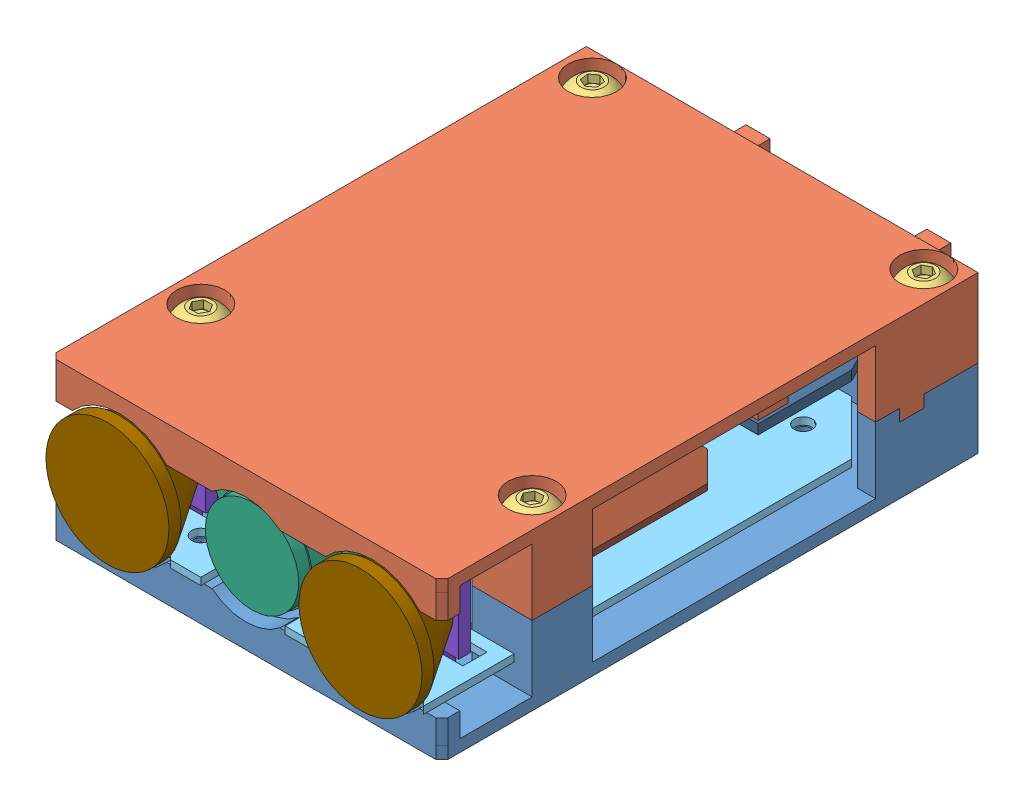
SolidWorks assembly master, configuration Default. Lengths in mm.
Overall size (68.08 28.52 102).
16 component instances, 11 part files, 37 mates.
Components (placement in the parent):
- chassi_master_inf-1: chassi_master_inf [Default] at (0 -0.5 -40) size (65 13 100)
- chassi_master_sup-1: chassi_master_sup [Default] at (0 25.5 -40) x (-1 0 0) z (0 0 1) size (65 15 100)
- Socket Button Head Screw_ISO-6: Socket Button Head Screw_ISO [ISO 7380 - M4 x 16 --- 16N] at (-27.5 25.1 -15) x (0 -1 0) z (0.03716 0 0.999309) size (18.2 7.6 7.6)
- Socket Button Head Screw_ISO-7: Socket Button Head Screw_ISO [ISO 7380 - M4 x 16 --- 16N] at (27.5 25.1 -15) x (0 -1 0) z (0.045545 0 0.998962) size (18.2 7.6 7.6)
- SUB9_macho-1: SUB9_macho [Default] at (0 6 -84) x (-1 0 0) z (0 0 -1) size (31 12.5 11.5)
- Socket Button Head Screw_ISO-8: Socket Button Head Screw_ISO [ISO 7380 - M4 x 16 --- 16N] at (-27.5 25.1 -80) x (0 -1 0) z (0.606475 0 0.795103) size (18.2 7.6 7.6)
- Socket Button Head Screw_ISO-9: Socket Button Head Screw_ISO [ISO 7380 - M4 x 16 --- 16N] at (27.5 25.1 -80) x (0 -1 0) z (-0.999509 0 -0.031349) size (18.2 7.6 7.6)
- PCB_master-1: PCB_master [Default] at (0 5.5 -34.5) size (60 1.2 80)
- camera-1: camera [Default] at (0 12.5 -19) x (0 1 0) z (0 0 1) size (21 26 23)
- bateria_9V-1: bateria_9V [Default] at (-14.65 14.5 -74.5) x (0 1 0) z (1 0 0) size (15.6 48.5 26.7)
- luz-1: luz [Default] at (-21 12.5 -5.8) size (11 16 3)
- luz-2: luz [Default] at (21 12.5 -5.8) size (11 16 3)
- lente-1: lente [Default] at (-21 12.5 -3.8) x (0 0 -1) z (0.999866 0.016372 0) size (10.8 20.4 20.4)
- lente-2: lente [Default] at (21 12.5 -3.8) x (0 0 -1) z (0.805945 0.59199 0) size (10.8 20.4 20.4)
- PCB_master2-1: PCB_master2 [Default] at (14.5 19.5 -59.25) x (0 0 1) z (1 0 0) size (18.5 1.6 31)
- XBee-1: XBee [Default] at (14.2823 10.9107 -38.7844) size (22 11 26)
Mates (geometry in assembly coordinates):
- Parallel3: parallel: plane of chassi_master_inf-1 through (-32.5 1.5 5) normal (0 1 0)
- Coincident38: coincident anti-aligned: plane of chassi_master_inf-1 through (-32.5 12.5 -20) normal (0 1 0); plane of chassi_master_sup-1 through (-32.5 12.5 -20) normal (0 -1 0)
- Coincident39: coincident aligned: plane of chassi_master_inf-1 through (-32.5 1.5 5) normal (0 0 1); plane of chassi_master_sup-1 through (32.5 23.5 5) normal (0 0 1)
- Coincident40: coincident aligned: plane of chassi_master_inf-1 through (-32.5 1.5 -85) normal (-1 0 0); plane of chassi_master_sup-1 through (-32.5 23.5 -85) normal (-1 0 0)
- Concentric262: concentric aligned: cylinder of chassi_master_inf-1; cylinder of SUB9_macho-1
- Concentric263: concentric aligned: cylinder of chassi_master_inf-1; cylinder of SUB9_macho-1
- Coincident513: coincident anti-aligned: plane of chassi_master_inf-1 through (-13 8.5 -84) normal (0 0 -1); plane of SUB9_macho-1 through (15.5 -0.25 -84) normal (0 0 1)
- Concentric264: concentric aligned: unknown of chassi_master_sup-1
- Concentric265: concentric aligned: unknown of chassi_master_sup-1
- Coincident514: coincident anti-aligned: unknown of chassi_master_sup-1
- Coincident515: coincident anti-aligned: unknown of chassi_master_sup-1
- Concentric266: concentric aligned: cylinder of chassi_master_inf-1; cylinder of PCB_master-1
- Concentric267: concentric aligned: cylinder of chassi_master_inf-1; cylinder of PCB_master-1
- Coincident516: coincident anti-aligned: plane of chassi_master_inf-1 through (10.5 5.5 2) normal (0 1 0); plane of PCB_master-1 through (-30 5.5 -20.5) normal (0 -1 0)
- Width1: width: plane of camera-1 through (-10.5 23 -3) normal (0 1 0); plane of camera-1 through (-10.5 2 -3) normal (0 -1 0); plane of chassi_master_inf-1 through (-32.5 1.5 5) normal (0 1 0); plane of chassi_master_sup-1 through (32.5 23.5 5) normal (0 -1 0)
- Width2: width: plane of camera-1 through (10.5 2 -3) normal (1 0 0); plane of camera-1 through (-10.5 2 -3) normal (-1 0 0); plane of chassi_master_inf-1 through (18.5 10.5 -13) normal (-1 0 0); plane of chassi_master_sup-1 through (-18.5 10.5 -13) normal (1 0 0)
- Coincident518: coincident anti-aligned: plane of PCB_master-1 through (-10.5 -3.3 -19) normal (0 0 1); plane of camera-1 through (10.5 12.5 -19) normal (0 0 -1)
- Coincident519: coincident anti-aligned: plane of PCB_master-1 through (-30 6.7 -20.5) normal (0 1 0); plane of bateria_9V-1 through (-28 6.7 -26) normal (0 -1 0)
- Distance2: distance = 2 mm aligned: plane of PCB_master-1 through (-30 6.7 -74.5) normal (-1 0 0); plane of bateria_9V-1 through (-28 6.7 -26) normal (-1 0 0)
- Coincident533: coincident aligned: plane of PCB_master-1 through (-30 6.7 -74.5) normal (0 0 -1); plane of bateria_9V-1 through (-1.3 6.7 -74.5) normal (0 0 -1)
- Concentric268: concentric anti-aligned: cylinder of luz-1; cylinder of lente-1
- Concentric269: concentric anti-aligned: cylinder of luz-2; cylinder of lente-2
- Coincident522: coincident anti-aligned: plane of luz-2 through (15.5 2 -3.8) normal (0 0 1); plane of lente-2 through (17.3168 9.7946 -3.8) normal (0 0 -1)
- Coincident524: coincident anti-aligned: plane of luz-1 through (-26.5 2 -3.8) normal (0 0 1); plane of lente-1 through (-25.5694 12.4252 -3.8) normal (0 0 -1)
- Coincident525: coincident aligned: plane of luz-1 through (-26.5 2 -5.8) normal (0 0 -1); plane of luz-2 through (15.5 2 -5.8) normal (0 0 -1)
- Coincident526: coincident aligned: plane of luz-1 through (-26.5 18 -3.8) normal (0 1 0); plane of luz-2 through (15.5 18 -3.8) normal (0 1 0)
- Symmetric1: symmetric aligned: plane of chassi_master_inf-1 through (32.5 12.5 -20) normal (0 1 0); plane of luz-2 through (15.5 18 -3.8) normal (0 1 0); plane of luz-2 through (24 7 -3.8) normal (0 -1 0)
- Concentric270: concentric aligned: unknown of chassi_master_sup-1
- Concentric271: concentric aligned: unknown of chassi_master_sup-1
- Coincident527: coincident anti-aligned: unknown of chassi_master_sup-1
- Coincident528: coincident anti-aligned: unknown of chassi_master_sup-1
- Distance4: distance = 2 mm aligned: plane of chassi_master_inf-1 through (-32.5 1.5 5) normal (0 0 1); plane of lente-2 through (12.7794 6.4617 7) normal (0 0 1)
- Distance5: distance = 6 mm aligned: plane of chassi_master_inf-1 through (32.5 1.5 -85) normal (1 0 0); plane of luz-2 through (26.5 7 -3.8) normal (1 0 0)
- Distance6: distance = 6 mm aligned: plane of chassi_master_inf-1 through (-32.5 1.5 -85) normal (-1 0 0); plane of luz-1 through (-26.5 7 -3.8) normal (-1 0 0)
- Coincident534: coincident anti-aligned: plane of chassi_master_sup-1 through (29.5 19.5 -50.5) normal (0 -1 0); plane of PCB_master2-1 through (-1 19.5 -50) normal (0 1 0)
- Concentric274: concentric aligned: cylinder of chassi_master_sup-1; cylinder of PCB_master2-1
- Concentric275: concentric aligned: cylinder of chassi_master_sup-1; cylinder of PCB_master2-1
